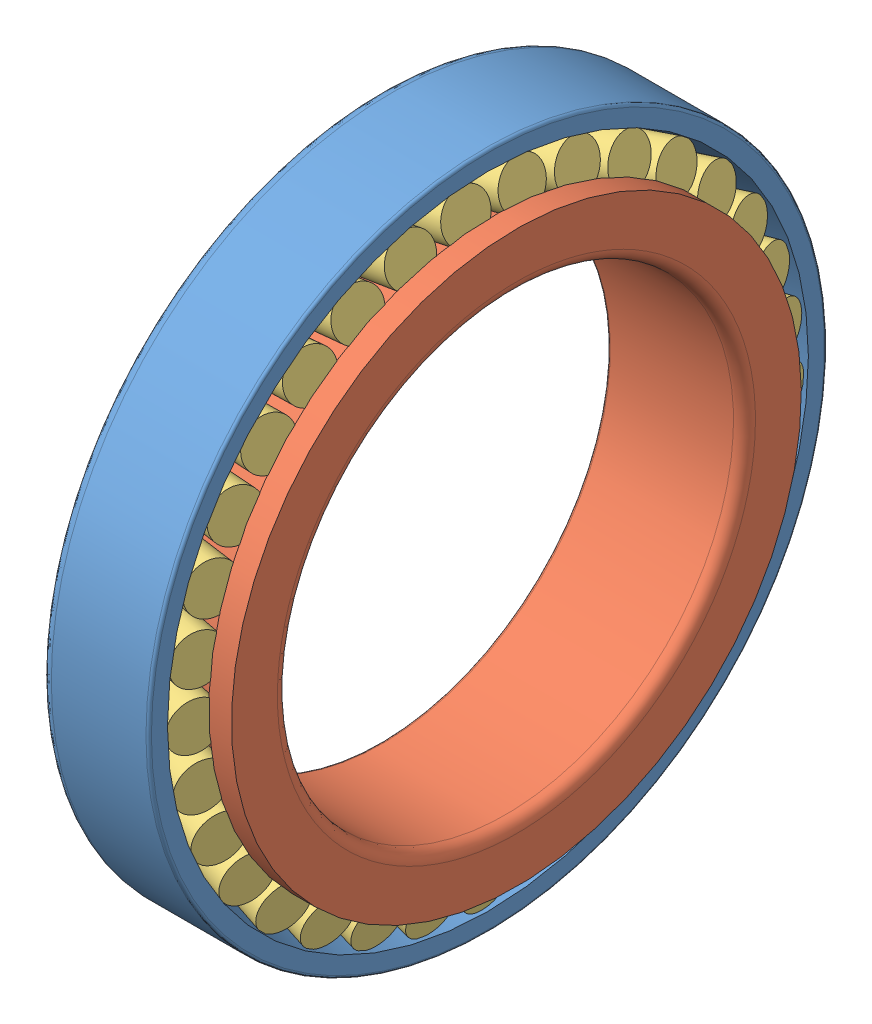
SolidWorks assembly Rear Bearing, configuration Default. Lengths in mm.
Overall size (19.05 99.76 99.68).
3 component instances, 3 part files, 4 mates.
Components (placement in the parent):
- Rear Cup-1: Rear Cup [Default] at origin size (15.08 94.46 94.46)
- Rear Cone-1: Rear Cone [Default] x (1 0 0) z (0 0.131216 -0.991354) size (19.05 79.33 79.33)
- Rear Rollers-1: Rear Rollers [Default] x (1 0 0) z (0 0.131216 -0.991354) size (15.2 88.88 88.79)
Mates (geometry in assembly coordinates):
- Coincident1: coordinate: point of Rear Cone-1; point of Rear Rollers-1
- Concentric1: concentric aligned: cylinder of Rear Cone-1 through (17.1298 0 0) axis (-1 0 0) radius 31.75; cylinder of Rear Cup-1 through (8.1128 0 0) axis (-1 0 0) radius 47.2288
- Coincident6: coincident aligned: plane of Rear Cup-1 through (0 0 43.0259) normal (-1 0 0); plane of Rear Cone-1 through (0 4.4841 -33.8777) normal (-1 0 0)
- Coincident5: coordinate: point of Rear Cup-1; point of assembly
